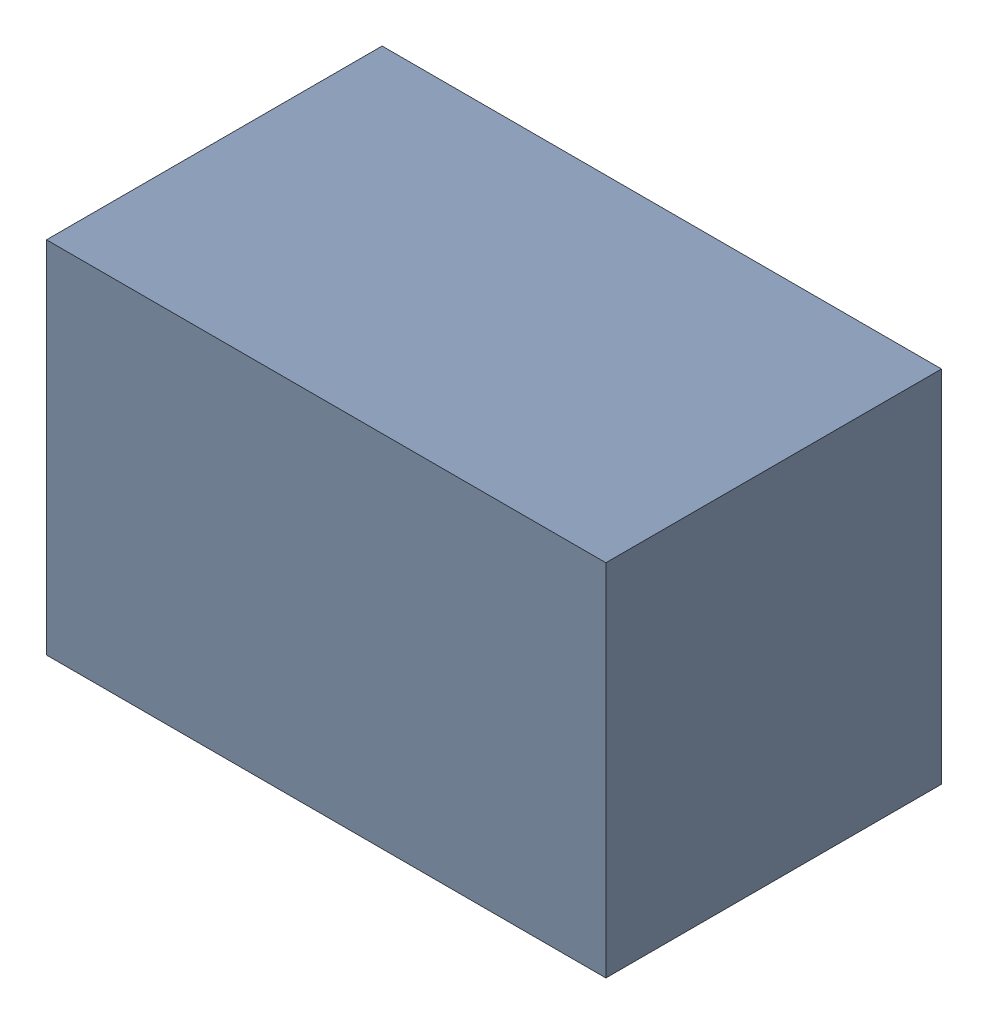
SolidWorks assembly C52, configuration Default. Lengths in mm.
Overall size (2.1 1.35 1.26).
2 component instances, 1 part files, 0 mates.
Components (placement in the parent):
- 407985824-1: 407985824 [Default] at (30.988 25.1206 0.0127) size (2.1 1.35 1.26)
  - Extruded_2-1: Extruded_2 [Default] at origin size (2.1 1.35 1.26)
